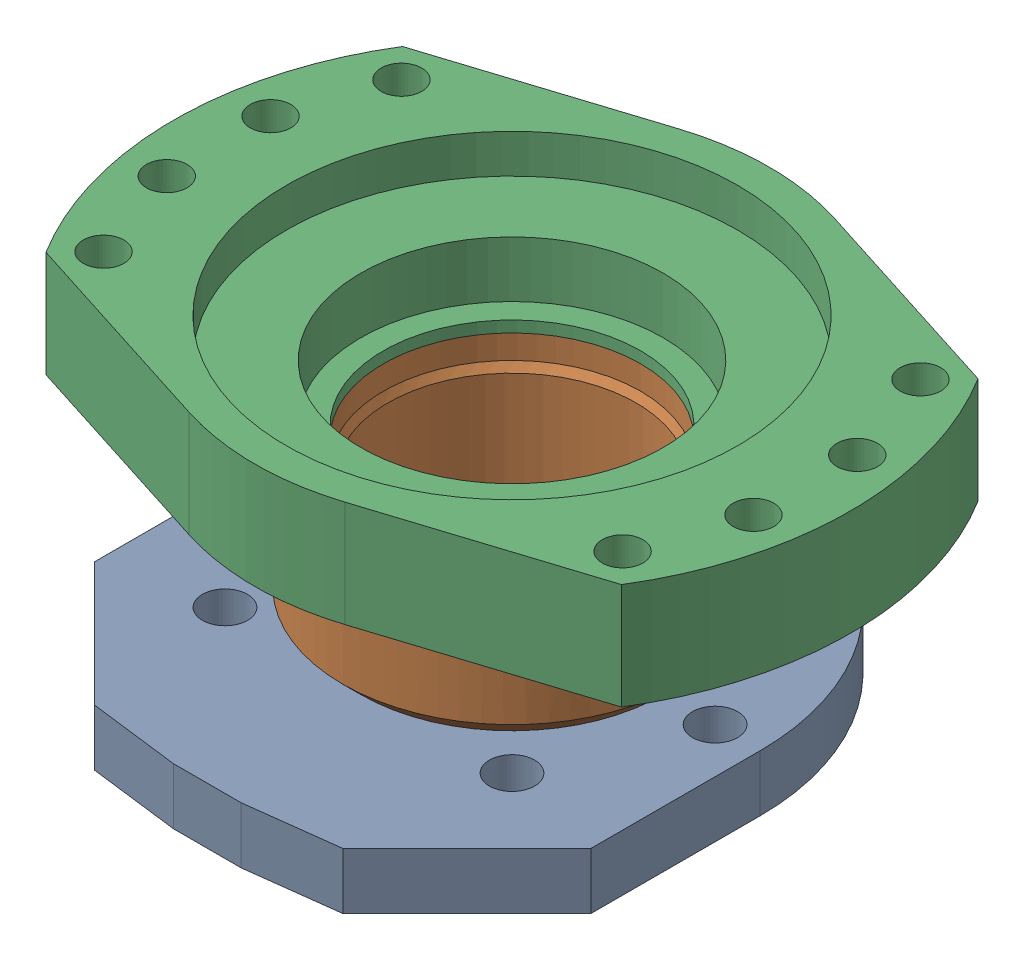
SolidWorks assembly g1_3_1_1_1_1, configuration 默认. Lengths in mm.
Overall size (300 154 249).
3 component instances, 3 part files, 0 mates.
Components (placement in the parent):
- g1_3_1_1_1_1-1_af0-1: g1_3_1_1_1_1-1_af0 [默认] at origin size (220 42 245)
- g1_3_1_1_1_1-2_af0-1: g1_3_1_1_1_1-2_af0 [默认] at (0 50 0) size (150 65 150)
- g1_3_1_1_1_1-3_af0-1: g1_3_1_1_1_1-3_af0 [默认] at (0 140 0) size (300 47 228)
